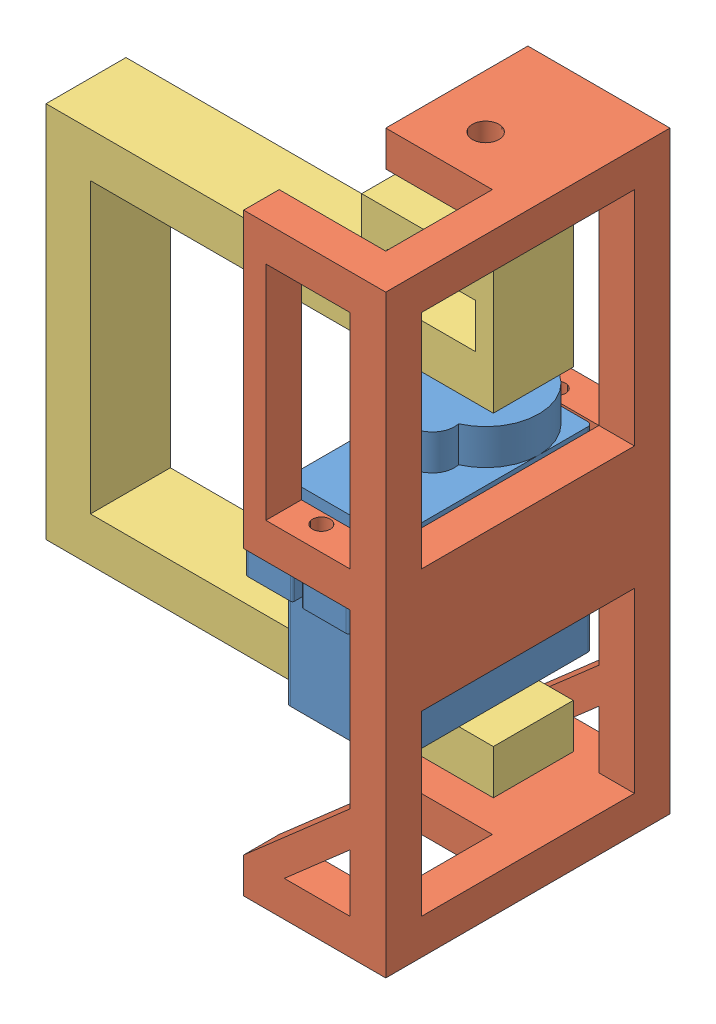
SolidWorks assembly Assem1, configuration Default. Lengths in mm.
Overall size (55 66.87 32).
3 component instances, 3 part files, 8 mates.
Components (placement in the parent):
- Towerpro Micro Servo 9g-1: Towerpro Micro Servo 9g [Varsayılan] at (-40.7154 -18.5349 23.8865) size (12 30 32)
- Part2-1: Part2 [Default] at (-40.7154 -1.0349 23.8865) x (1 0 0) z (0 1 0) size (16 32 66.87)
- Copy of Part3^Assem1-1: Copy of Part3^Assem1 [Default] at (-40.7154 11.4651 23.8865) x (1 0 0) z (0 1 0) size (50.36 9 51.5) (virtual)
Mates (geometry in assembly coordinates):
- InPlace1: in place: plane of Towerpro Micro Servo 9g-1 through (-35.2154 -1.0349 39.3865) normal (0 1 0); plane of ? through (0 -1.0349 0) normal (0 1 0); moOrthogonalPlaneRef_w of Towerpro Micro Servo 9g-1 through (-35.2154 -1.0349 39.3865) normal (0 1 0); plane of ? through (0 -1.0349 0) normal (0 0 -1); plane of Towerpro Micro Servo 9g-1 through (-35.2154 -1.0349 39.3865) normal (0 1 0); plane of ? through (0 -1.0349 0) normal (1 0 0); plane of Towerpro Micro Servo 9g-1 through (-35.2154 -1.0349 39.3865) normal (0 1 0); unknown of Part2-1
- Coincident1: coincident aligned: plane of Towerpro Micro Servo 9g-1; plane of Part2-1
- Coincident2: coincident aligned: moOrthogonalPlaneRef_w of Towerpro Micro Servo 9g-1 through (-40.7154 -1.0349 23.8865) normal (0 0 -1); plane of Part2-1 through (-40.7154 -1.0349 23.8865) normal (0 0 -1)
- Coincident3: coincident anti-aligned: moOrthogonalPlaneRef_w of Towerpro Micro Servo 9g-1 through (-40.7154 -1.0349 23.8865) normal (-1 0 0); plane of Part2-1 through (-40.7154 -1.0349 23.8865) normal (1 0 0)
- InPlace2: in place: plane of Towerpro Micro Servo 9g-1 through (-40.7154 11.4651 18.6365) normal (0 1 0); plane of ? through (0 11.4651 0) normal (0 1 0); plane of Towerpro Micro Servo 9g-1 through (-40.7154 11.4651 18.6365) normal (0 1 0); plane of ? through (0 11.4651 0) normal (0 0 -1); plane of Towerpro Micro Servo 9g-1 through (-40.7154 11.4651 18.6365) normal (0 1 0); plane of ? through (0 11.4651 0) normal (1 0 0); plane of Towerpro Micro Servo 9g-1 through (-40.7154 11.4651 18.6365) normal (0 1 0); unknown of Copy of Part3^Assem1-1
- Coincident4: coincident aligned: plane of Towerpro Micro Servo 9g-1; plane of Copy of Part3^Assem1-1
- Coincident5: coincident aligned: moOrthogonalPlaneRef_w of Towerpro Micro Servo 9g-1 through (-40.7154 11.4651 23.8865) normal (0 0 -1); plane of Copy of Part3^Assem1-1 through (-40.7154 11.4651 23.8865) normal (0 0 -1)
- Coincident6: coincident anti-aligned: moOrthogonalPlaneRef_w of Towerpro Micro Servo 9g-1 through (-40.7154 11.4651 23.8865) normal (-1 0 0); plane of Copy of Part3^Assem1-1 through (-40.7154 11.4651 23.8865) normal (1 0 0)
